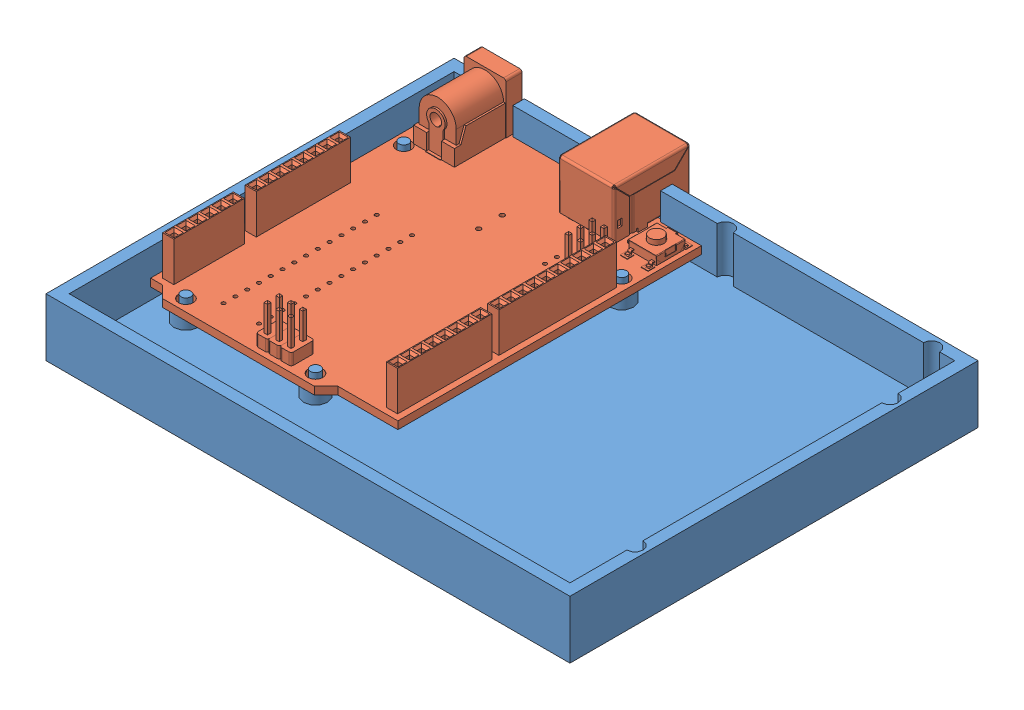
SolidWorks assembly Enclosure, configuration Default. Lengths in mm.
Overall size (113 17.7 92.44).
2 component instances, 2 part files, 3 mates.
Components (placement in the parent):
- EnclosureBase-1: EnclosureBase [Default] at origin size (113 12.5 88)
- arduino uno-1: arduino uno [Default] at (0 6.65 -83.595) x (-1 0 0) z (0 0 -1) size (53.34 15.25 74.93)
Mates (geometry in assembly coordinates):
- Coincident1: coincident aligned: plane of EnclosureBase-1 through (-2.5 2.5 -85.5) normal (0 0 -1); plane of arduino uno-1 through (3.675 17.15 -85.5) normal (0 0 -1)
- Coincident2: coincident anti-aligned: plane of EnclosureBase-1 through (0 165.7236 0) normal (1 0 0); plane of arduino uno-1 through (0 5 -83.595) normal (-1 0 0)
- Distance1: distance = 2.5 mm: point of arduino uno-1; plane of EnclosureBase-1 through (0 2.5 0) normal (0 1 0)
